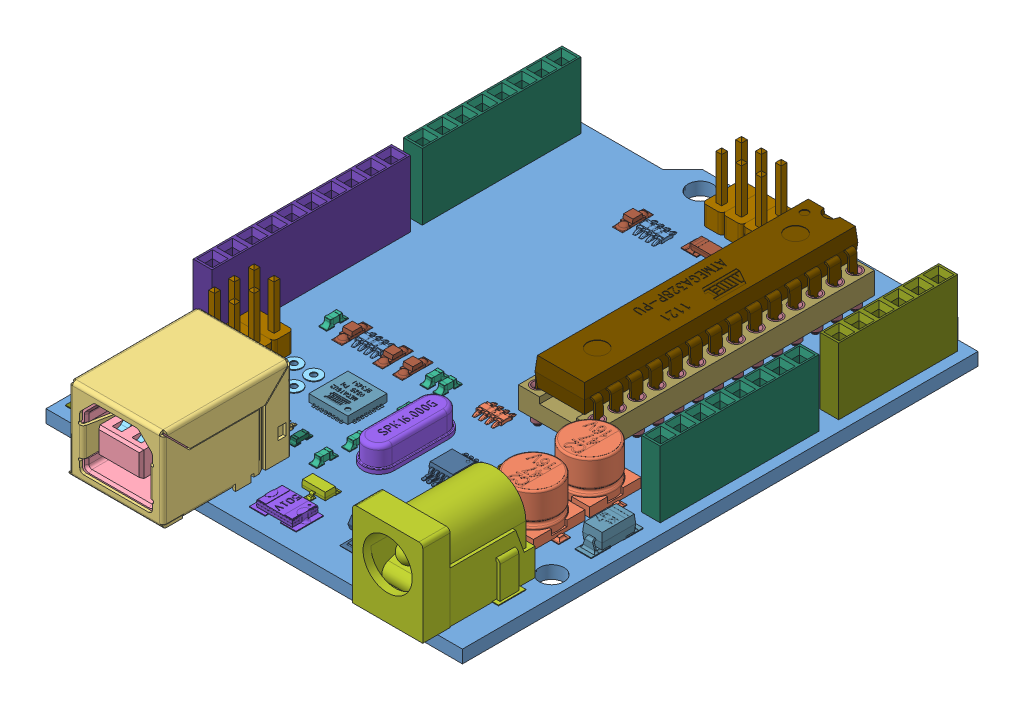
SolidWorks assembly 100001-10001-3-0, configuration Default. Lengths in mm.
Overall size (53.34 15.25 74.97).
87 component instances, 35 part files, 133 mates.
Components (placement in the parent):
- unoboar100001-10001-3-0 blue.SL100001-10001-3-0PRT-1: unoboar100001-10001-3-0 blue.SL100001-10001-3-0PRT [Default] at origin size (53.34 1.65 68.58)
- 47uf CAP 100001-10001-3-0case.SL100001-10001-3-0PRT-1: 47uf CAP 100001-10001-3-0case.SL100001-10001-3-0PRT [Default] at (-9.4141 0 -18.4991) x (0 0 -1) z (1 0 0) size (6.6 5.81 8)
- USB type b.SL100001-10001-3-0PRT.SL100001-10001-3-0ASM-1: USB type b.SL100001-10001-3-0PRT.SL100001-10001-3-0ASM [Default] at (-38.02 0.43 6.35) size (14.34 15.2 16.54)
  - USB SHELL.SL100001-10001-3-0PRT-1: USB SHELL.SL100001-10001-3-0PRT [Default] at origin size (14.34 15.2 16.54)
  - USB core.SL100001-10001-3-0PRT-1: USB core.SL100001-10001-3-0PRT [Default] at origin size (11.3 10.68 15.75)
  - usb top contact.SL100001-10001-3-0PRT-1: usb top contact.SL100001-10001-3-0PRT [Default] at (1.25 6.09 -0.38) size (1 9.67 13.76)
  - usb btm contact.SL100001-10001-3-0PRT-1: usb btm contact.SL100001-10001-3-0PRT [Default] at (1.25 4.41 -0.38) size (1 6.84 11.76)
  - usb btm contact.SL100001-10001-3-0PRT-2: usb btm contact.SL100001-10001-3-0PRT [Default] at (-1.25 4.41 -0.38) size (1 6.84 11.76)
  - usb top contact.SL100001-10001-3-0PRT-2: usb top contact.SL100001-10001-3-0PRT [Default] at (-1.25 6.09 -0.38) size (1 9.67 13.76)
- power jack.SL100001-10001-3-0PRT-1: power jack.SL100001-10001-3-0PRT [Default] at (-7.675 0 1.905) size (11.2 15.2 15.9)
- 47uf CAP 100001-10001-3-0case.SL100001-10001-3-0PRT-2: 47uf CAP 100001-10001-3-0case.SL100001-10001-3-0PRT [Default] at (-9.4141 0 -25.7132) x (0 0 -1) z (1 0 0) size (6.6 5.81 8)
- crystal.sl100001-10001-3-0prt-1: crystal.sl100001-10001-3-0prt [Default] at (-26.162 0 -18.923) x (1 0 0) z (0 0 -1) size (4 5 11)
- 2pin_hea100001-10001-3-0er__02.sl100001-10001-3-0prt-1: 2pin_hea100001-10001-3-0er__02.sl100001-10001-3-0prt [Default] at (-46.23 0 -15.75) size (5 11.75 2.54)
- nano - reg.SL100001-10001-3-0PRT-1: nano - reg.SL100001-10001-3-0PRT [Default] at (-17.399 0 -7.747) size (6.5 1.69 8.3)
- le100001-10001-3-0.SL100001-10001-3-0PRT-1: le100001-10001-3-0.SL100001-10001-3-0PRT [Default] at (-34.29 0 -27.94) x (0 0 1) z (-1 0 0) size (4 0.86 1.35)
- 2pin_hea100001-10001-3-0er__02.sl100001-10001-3-0prt-7: 2pin_hea100001-10001-3-0er__02.sl100001-10001-3-0prt [Default] at (-30.43 0 -64.91) x (0 0 1) z (-1 0 0) size (5 11.75 2.54)
- 100001-10001-3-0ip28.SL100001-10001-3-0ASM-1: 100001-10001-3-0ip28.SL100001-10001-3-0ASM [Default] at (-16.383 1.5 -46.355) x (0 0 -1) z (1 0 0) size (35.48 7.37 10.1)
  - 100001-10001-3-0ip28.SL100001-10001-3-0PRT-1: 100001-10001-3-0ip28.SL100001-10001-3-0PRT [Default] at origin size (35.48 2.8 10.1)
  - 100001-10001-3-0ip socket pin.SL100001-10001-3-0PRT-1: 100001-10001-3-0ip socket pin.SL100001-10001-3-0PRT [Default] at (16.51 2.8 -3.81) size (1.7 7.37 1.7)
  - 100001-10001-3-0ip socket pin.SL100001-10001-3-0PRT-2: 100001-10001-3-0ip socket pin.SL100001-10001-3-0PRT [Default] at (16.51 2.8 3.81) size (1.7 7.37 1.7)
  - 100001-10001-3-0ip socket pin.SL100001-10001-3-0PRT-3: 100001-10001-3-0ip socket pin.SL100001-10001-3-0PRT [Default] at (13.97 2.8 -3.81) size (1.7 7.37 1.7)
  - 100001-10001-3-0ip socket pin.SL100001-10001-3-0PRT-4: 100001-10001-3-0ip socket pin.SL100001-10001-3-0PRT [Default] at (13.97 2.8 3.81) size (1.7 7.37 1.7)
  - 100001-10001-3-0ip socket pin.SL100001-10001-3-0PRT-5: 100001-10001-3-0ip socket pin.SL100001-10001-3-0PRT [Default] at (11.43 2.8 -3.81) size (1.7 7.37 1.7)
  - 100001-10001-3-0ip socket pin.SL100001-10001-3-0PRT-6: 100001-10001-3-0ip socket pin.SL100001-10001-3-0PRT [Default] at (11.43 2.8 3.81) size (1.7 7.37 1.7)
  - 100001-10001-3-0ip socket pin.SL100001-10001-3-0PRT-7: 100001-10001-3-0ip socket pin.SL100001-10001-3-0PRT [Default] at (8.89 2.8 -3.81) size (1.7 7.37 1.7)
  - 100001-10001-3-0ip socket pin.SL100001-10001-3-0PRT-8: 100001-10001-3-0ip socket pin.SL100001-10001-3-0PRT [Default] at (8.89 2.8 3.81) size (1.7 7.37 1.7)
  - 100001-10001-3-0ip socket pin.SL100001-10001-3-0PRT-9: 100001-10001-3-0ip socket pin.SL100001-10001-3-0PRT [Default] at (6.35 2.8 -3.81) size (1.7 7.37 1.7)
  - 100001-10001-3-0ip socket pin.SL100001-10001-3-0PRT-10: 100001-10001-3-0ip socket pin.SL100001-10001-3-0PRT [Default] at (6.35 2.8 3.81) size (1.7 7.37 1.7)
  - 100001-10001-3-0ip socket pin.SL100001-10001-3-0PRT-11: 100001-10001-3-0ip socket pin.SL100001-10001-3-0PRT [Default] at (3.81 2.8 -3.81) size (1.7 7.37 1.7)
  - 100001-10001-3-0ip socket pin.SL100001-10001-3-0PRT-12: 100001-10001-3-0ip socket pin.SL100001-10001-3-0PRT [Default] at (3.81 2.8 3.81) size (1.7 7.37 1.7)
  - 100001-10001-3-0ip socket pin.SL100001-10001-3-0PRT-13: 100001-10001-3-0ip socket pin.SL100001-10001-3-0PRT [Default] at (1.27 2.8 -3.81) size (1.7 7.37 1.7)
  - 100001-10001-3-0ip socket pin.SL100001-10001-3-0PRT-14: 100001-10001-3-0ip socket pin.SL100001-10001-3-0PRT [Default] at (1.27 2.8 3.81) size (1.7 7.37 1.7)
  - 100001-10001-3-0ip socket pin.SL100001-10001-3-0PRT-15: 100001-10001-3-0ip socket pin.SL100001-10001-3-0PRT [Default] at (-1.27 2.8 -3.81) size (1.7 7.37 1.7)
  - 100001-10001-3-0ip socket pin.SL100001-10001-3-0PRT-16: 100001-10001-3-0ip socket pin.SL100001-10001-3-0PRT [Default] at (-1.27 2.8 3.81) size (1.7 7.37 1.7)
  - 100001-10001-3-0ip socket pin.SL100001-10001-3-0PRT-17: 100001-10001-3-0ip socket pin.SL100001-10001-3-0PRT [Default] at (-3.81 2.8 -3.81) size (1.7 7.37 1.7)
  - 100001-10001-3-0ip socket pin.SL100001-10001-3-0PRT-18: 100001-10001-3-0ip socket pin.SL100001-10001-3-0PRT [Default] at (-3.81 2.8 3.81) size (1.7 7.37 1.7)
  - 100001-10001-3-0ip socket pin.SL100001-10001-3-0PRT-19: 100001-10001-3-0ip socket pin.SL100001-10001-3-0PRT [Default] at (-6.35 2.8 -3.81) size (1.7 7.37 1.7)
  - 100001-10001-3-0ip socket pin.SL100001-10001-3-0PRT-20: 100001-10001-3-0ip socket pin.SL100001-10001-3-0PRT [Default] at (-6.35 2.8 3.81) size (1.7 7.37 1.7)
  - 100001-10001-3-0ip socket pin.SL100001-10001-3-0PRT-21: 100001-10001-3-0ip socket pin.SL100001-10001-3-0PRT [Default] at (-8.89 2.8 -3.81) size (1.7 7.37 1.7)
  - 100001-10001-3-0ip socket pin.SL100001-10001-3-0PRT-22: 100001-10001-3-0ip socket pin.SL100001-10001-3-0PRT [Default] at (-8.89 2.8 3.81) size (1.7 7.37 1.7)
  - 100001-10001-3-0ip socket pin.SL100001-10001-3-0PRT-23: 100001-10001-3-0ip socket pin.SL100001-10001-3-0PRT [Default] at (-11.43 2.8 -3.81) size (1.7 7.37 1.7)
  - 100001-10001-3-0ip socket pin.SL100001-10001-3-0PRT-24: 100001-10001-3-0ip socket pin.SL100001-10001-3-0PRT [Default] at (-11.43 2.8 3.81) size (1.7 7.37 1.7)
  - 100001-10001-3-0ip socket pin.SL100001-10001-3-0PRT-25: 100001-10001-3-0ip socket pin.SL100001-10001-3-0PRT [Default] at (-13.97 2.8 -3.81) size (1.7 7.37 1.7)
  - 100001-10001-3-0ip socket pin.SL100001-10001-3-0PRT-26: 100001-10001-3-0ip socket pin.SL100001-10001-3-0PRT [Default] at (-13.97 2.8 3.81) size (1.7 7.37 1.7)
  - 100001-10001-3-0ip socket pin.SL100001-10001-3-0PRT-27: 100001-10001-3-0ip socket pin.SL100001-10001-3-0PRT [Default] at (-16.51 2.8 -3.81) size (1.7 7.37 1.7)
  - 100001-10001-3-0ip socket pin.SL100001-10001-3-0PRT-28: 100001-10001-3-0ip socket pin.SL100001-10001-3-0PRT [Default] at (-16.51 2.8 3.81) size (1.7 7.37 1.7)
- 2pin_hea100001-10001-3-0er__02.sl100001-10001-3-0prt-8: 2pin_hea100001-10001-3-0er__02.sl100001-10001-3-0prt [Default] at (-27.89 0 -64.91) x (0 0 1) z (-1 0 0) size (5 11.75 2.54)
- 2pin_hea100001-10001-3-0er__02.sl100001-10001-3-0prt-9: 2pin_hea100001-10001-3-0er__02.sl100001-10001-3-0prt [Default] at (-25.35 0 -64.91) x (0 0 1) z (-1 0 0) size (5 11.75 2.54)
- 2pin_hea100001-10001-3-0er__02.sl100001-10001-3-0prt-5: 2pin_hea100001-10001-3-0er__02.sl100001-10001-3-0prt [Default] at (-46.23 0 -18.29) size (5 11.75 2.54)
- 2pin_hea100001-10001-3-0er__02.sl100001-10001-3-0prt-6: 2pin_hea100001-10001-3-0er__02.sl100001-10001-3-0prt [Default] at (-46.23 0 -20.83) size (5 11.75 2.54)
- atmega16u2.SL100001-10001-3-0PRT-1: atmega16u2.SL100001-10001-3-0PRT [Default] at (-34.671 0.06 -20) x (1 0 0) z (0 0 -1) size (5.5 1.01 5.5)
- le100001-10001-3-0.SL100001-10001-3-0PRT-2: le100001-10001-3-0.SL100001-10001-3-0PRT [Default] at (-36.83 0 -27.94) x (0 0 1) z (-1 0 0) size (4 0.86 1.35)
- le100001-10001-3-0.SL100001-10001-3-0PRT-3: le100001-10001-3-0.SL100001-10001-3-0PRT [Default] at (-42.037 0 -27.94) x (0 0 1) z (-1 0 0) size (4 0.86 1.35)
- le100001-10001-3-0.SL100001-10001-3-0PRT-4: le100001-10001-3-0.SL100001-10001-3-0PRT [Default] at (-36.576 0 -58.42) x (0 0 1) z (-1 0 0) size (4 0.86 1.35)
- 8 PORT HEA100001-10001-3-0ER.SL100001-10001-3-0PRT-3: 8 PORT HEA100001-10001-3-0ER.SL100001-10001-3-0PRT [Default] at (-50.8 0 -45.72) x (0 0 -1) z (1 0 0) size (20.32 10.51 2.41)
- 8 PORT HEA100001-10001-3-0ER.SL100001-10001-3-0PRT-4: 8 PORT HEA100001-10001-3-0ER.SL100001-10001-3-0PRT [Default] at (-2.54 0 -27.94) x (0 0 -1) z (1 0 0) size (20.32 10.51 2.41)
- 6 PORT HEA100001-10001-3-0ER.SL100001-10001-3-0PRT-3: 6 PORT HEA100001-10001-3-0ER.SL100001-10001-3-0PRT [Default] at (-2.54 0 -50.8) x (0 0 -1) z (1 0 0) size (15.24 10.51 2.41)
- 10 PORT HEA100001-10001-3-0ER.SL100001-10001-3-0PRT-1: 10 PORT HEA100001-10001-3-0ER.SL100001-10001-3-0PRT [Default] at (-50.8 0 -18.796) x (0 0 -1) z (1 0 0) size (25.4 10.51 2.41)
- ATMEL328P.SL100001-10001-3-0PRT-1: ATMEL328P.SL100001-10001-3-0PRT [Default] at (-16.383 4.3 -46.355) x (0 0 -1) z (1 0 0) size (35 7.27 7.87)
- 102 RESISTOR PACK.SL100001-10001-3-0PRT-1: 102 RESISTOR PACK.SL100001-10001-3-0PRT [Default] at (-33.782 0 -58.42) size (3.2 0.46 3)
- 102 RESISTOR PACK.SL100001-10001-3-0PRT-2: 102 RESISTOR PACK.SL100001-10001-3-0PRT [Default] at (-39.37 0 -27.94) size (3.2 0.46 3)
- 103 RESISTOR PACK.SL100001-10001-3-0PRT-3: 103 RESISTOR PACK.SL100001-10001-3-0PRT [Default] at (-23.876 0 -27.94) size (3.2 0.46 3)
- 220 RESISTOR PACK.SL100001-10001-3-0PRT-1: 220 RESISTOR PACK.SL100001-10001-3-0PRT [Default] at (-36.83 0 -12.827) size (3.2 0.46 3)
- 16mhz crystal - measure100001-10001-3-0.SL100001-10001-3-0PRT-1: 16mhz crystal - measure100001-10001-3-0.SL100001-10001-3-0PRT [Default] at (-24.892 0 -41.275) x (0 0 -1) z (1 0 0) size (3.4 0.8 2)
- PA100001-10001-3-0S001.SL100001-10001-3-0PRT-1: PA100001-10001-3-0S001.SL100001-10001-3-0PRT [Default] at (-39.878 0.1 -18.288) x (-1 0 0) z (0 0 1) size (4.54 0.1 4.54)
- 603 cap on pa100001-10001-3-0.SL100001-10001-3-0PRT-1: 603 cap on pa100001-10001-3-0.SL100001-10001-3-0PRT [Default] at (-44.45 0 -27.94) x (0 0 -1) z (1 0 0) size (2.76 0.9 1.12)
- ssot3.SL100001-10001-3-0PRT-1: ssot3.SL100001-10001-3-0PRT [Default] at (-26.5 0 -8.128) x (-1 0 0) z (0 0 -1) size (3 1.13 3.09)
- mf-msmf050-2.SL100001-10001-3-0PRT-1: mf-msmf050-2.SL100001-10001-3-0PRT [Default] at (-26.5 0 -4.064) size (5.77 1.02 3.72)
- 603 cap on pa100001-10001-3-0.SL100001-10001-3-0PRT-2: 603 cap on pa100001-10001-3-0.SL100001-10001-3-0PRT [Default] at (-29.845 0 -27.94) x (0 0 -1) z (1 0 0) size (2.76 0.9 1.12)
- 603 cap on pa100001-10001-3-0.SL100001-10001-3-0PRT-3: 603 cap on pa100001-10001-3-0.SL100001-10001-3-0PRT [Default] at (-31.496 0 -27.94) x (0 0 -1) z (1 0 0) size (2.76 0.9 1.12)
- lmv358.SL100001-10001-3-0PRT-1: lmv358.SL100001-10001-3-0PRT [Default] at (-15.24 0 -21.971) x (0 0 -1) z (1 0 0) size (3.7 1.4 2.9)
- 603 cap on pa100001-10001-3-0.SL100001-10001-3-0PRT-4: 603 cap on pa100001-10001-3-0.SL100001-10001-3-0PRT [Default] at (-15.24 0 -18.415) size (2.76 0.9 1.12)
- 603 cap on pa100001-10001-3-0.SL100001-10001-3-0PRT-5: 603 cap on pa100001-10001-3-0.SL100001-10001-3-0PRT [Default] at (-29.845 0 -12.065) x (0 0 1) z (-1 0 0) size (2.76 0.9 1.12)
- 603 cap on pa100001-10001-3-0.SL100001-10001-3-0PRT-6: 603 cap on pa100001-10001-3-0.SL100001-10001-3-0PRT [Default] at (-29.591 0 -22.352) x (0 0 1) z (-1 0 0) size (2.76 0.9 1.12)
- 603 cap on pa100001-10001-3-0.SL100001-10001-3-0PRT-7: 603 cap on pa100001-10001-3-0.SL100001-10001-3-0PRT [Default] at (-29.591 0 -16.002) x (0 0 1) z (-1 0 0) size (2.76 0.9 1.12)
- 603 cap on pa100001-10001-3-0.SL100001-10001-3-0PRT-8: 603 cap on pa100001-10001-3-0.SL100001-10001-3-0PRT [Default] at (-41.91 0 -12.7) x (0 0 1) z (-1 0 0) size (2.76 0.9 1.12)
- lp2985100001-10001-3-0gkr.SL100001-10001-3-0PRT-1: lp2985100001-10001-3-0gkr.SL100001-10001-3-0PRT [Default] at (-20.32 0 -19.05) x (0 0 -1) z (1 0 0) size (5.85 1.1 3)
- c100001-10001-3-01206 100001-10001-3-0io100001-10001-3-0e.SL100001-10001-3-0PRT-1: c100001-10001-3-01206 100001-10001-3-0io100001-10001-3-0e.SL100001-10001-3-0PRT [Default] at (-27.94 0 -59.436) x (0 0 -1) z (1 0 0) size (2.07 0.96 5)
- c100001-10001-3-01206 100001-10001-3-0io100001-10001-3-0e.SL100001-10001-3-0PRT-2: c100001-10001-3-01206 100001-10001-3-0io100001-10001-3-0e.SL100001-10001-3-0PRT [Default] at (-46.228 0 -13.081) x (0 0 1) z (-1 0 0) size (2.07 0.96 5)
- 603 resistor.SL100001-10001-3-0PRT-1: 603 resistor.SL100001-10001-3-0PRT [Default] at (-29.591 0 -19.05) x (0 0 1) z (-1 0 0) size (2.36 0.61 1.03)
- blm21.SL100001-10001-3-0PRT-1: blm21.SL100001-10001-3-0PRT [Default] at (-45.085 0 -7.62) x (0 0 -1) z (1 0 0) size (2.76 0.95 1.32)
- m7 100001-10001-3-0io100001-10001-3-0e.SL100001-10001-3-0PRT-1: m7 100001-10001-3-0io100001-10001-3-0e.SL100001-10001-3-0PRT [Default] at (-2.794 0 -21.59) x (0 0 -1) z (1 0 0) size (6.66 2.35 2.5)
- MLC0603.SL100001-10001-3-0PRT-1: MLC0603.SL100001-10001-3-0PRT [Default] at (-33.655 0 -12.827) x (0 0 -1) z (1 0 0) size (2.36 0.6 1.03)
- MLC0603.SL100001-10001-3-0PRT-2: MLC0603.SL100001-10001-3-0PRT [Default] at (-39.37 0 -12.827) x (0 0 -1) z (1 0 0) size (2.36 0.6 1.03)
- RESET BUTTON.SL100001-10001-3-0ASM-1: RESET BUTTON.SL100001-10001-3-0ASM [Default] at (-49.403 0 -6.35) size (6.2 3.1 9.6)
  - RESET CORE.SL100001-10001-3-0PRT-1: RESET CORE.SL100001-10001-3-0PRT [Default] at (0 0.1 0) x (-1 0 0) z (0 0 -1) size (6.2 3.1 9.6)
  - RESET.SL100001-10001-3-0PRT-1: RESET.SL100001-10001-3-0PRT [Default] at (0 0.1 0) x (0 0 1) z (-1 0 0) size (7.3 2 6.2)
Mates (geometry in assembly coordinates):
- Distance1: distance = 1.905 mm aligned: plane of power jack.SL100001-10001-3-0PRT-1 through (-7.675 0 1.905) normal (0 0 1); plane of unoboar100001-10001-3-0 blue.SL100001-10001-3-0PRT-1 through (0 0 0) normal (0 0 1)
- Coincident2: coincident aligned: plane of unoboar100001-10001-3-0 blue.SL100001-10001-3-0PRT-1 through (0 0 0) normal (0 1 0); plane of power jack.SL100001-10001-3-0PRT-1 through (-7.675 0 1.905) normal (0 1 0)
- Coincident3: coincident anti-aligned: plane of unoboar100001-10001-3-0 blue.SL100001-10001-3-0PRT-1 through (0 0 0) normal (0 1 0); plane of USB type b.SL100001-10001-3-0PRT.SL100001-10001-3-0ASM-1/USB core.SL100001-10001-3-0PRT-1 through (-38.02 0 6.35) normal (0 -1 0)
- Distance2: distance = 6.35 mm aligned: plane of USB type b.SL100001-10001-3-0PRT.SL100001-10001-3-0ASM-1/USB SHELL.SL100001-10001-3-0PRT-1 through (-38.02 0.43 6.35) normal (0 0 1); plane of unoboar100001-10001-3-0 blue.SL100001-10001-3-0PRT-1 through (0 0 0) normal (0 0 1)
- Coincident5: coincident aligned: plane of unoboar100001-10001-3-0 blue.SL100001-10001-3-0PRT-1 through (0 0 0) normal (0 1 0); plane of 47uf CAP 100001-10001-3-0case.SL100001-10001-3-0PRT-1
- Parallel1: parallel anti-aligned: plane of unoboar100001-10001-3-0 blue.SL100001-10001-3-0PRT-1 through (0 0 0) normal (0 0 1); plane of 47uf CAP 100001-10001-3-0case.SL100001-10001-3-0PRT-1 through (-9.4141 0 -18.4991) normal (0 0 -1)
- Coincident7: coincident aligned: plane of 47uf CAP 100001-10001-3-0case.SL100001-10001-3-0PRT-1 through (-6.1141 1.5 -15.1991) normal (1 0 0); plane of 47uf CAP 100001-10001-3-0case.SL100001-10001-3-0PRT-2 through (-6.1141 1.5 -22.4132) normal (1 0 0)
- Coincident8: coincident anti-aligned: plane of unoboar100001-10001-3-0 blue.SL100001-10001-3-0PRT-1 through (0 0 0) normal (0 1 0); plane of 47uf CAP 100001-10001-3-0case.SL100001-10001-3-0PRT-2 through (-8.1891 0 -25.7132) normal (0 -1 0)
- Distance3: distance = 3.175 mm aligned: plane of power jack.SL100001-10001-3-0PRT-1 through (-3.175 10.5 -1.595) normal (1 0 0); plane of unoboar100001-10001-3-0 blue.SL100001-10001-3-0PRT-1 through (0 -1.65 0) normal (1 0 0)
- Distance4: distance = 32 mm aligned: plane of USB type b.SL100001-10001-3-0PRT.SL100001-10001-3-0ASM-1/USB SHELL.SL100001-10001-3-0PRT-1 through (-32 0.43 6.35) normal (1 0 0); plane of unoboar100001-10001-3-0 blue.SL100001-10001-3-0PRT-1 through (0 -1.65 0) normal (1 0 0)
- Coincident11: coincident anti-aligned: plane of unoboar100001-10001-3-0 blue.SL100001-10001-3-0PRT-1 through (0 0 0) normal (0 1 0); plane of crystal.sl100001-10001-3-0prt-1 through (-26.162 0 -22.423) normal (0 -1 0)
- Concentric1: concentric aligned: cylinder of unoboar100001-10001-3-0 blue.SL100001-10001-3-0PRT-1 through (-26.162 -10 -16.383) axis (0 1 0) radius 0.5; cylinder of crystal.sl100001-10001-3-0prt-1 through (-26.162 -2 -16.383) axis (0 1 0) radius 0.4
- Concentric2: concentric aligned: cylinder of unoboar100001-10001-3-0 blue.SL100001-10001-3-0PRT-1 through (-26.162 -10 -21.463) axis (0 1 0) radius 0.5; cylinder of crystal.sl100001-10001-3-0prt-1 through (-26.162 -2 -21.463) axis (0 1 0) radius 0.4
- Coincident12: coincident anti-aligned: plane of unoboar100001-10001-3-0 blue.SL100001-10001-3-0PRT-1 through (0 0 0) normal (0 1 0); plane of 2pin_hea100001-10001-3-0er__02.sl100001-10001-3-0prt-1 through (-44.23 0 -14.98) normal (0 -1 0)
- Distance5: distance = 15.75 mm aligned: plane of 2pin_hea100001-10001-3-0er__02.sl100001-10001-3-0prt-1 through (-46.23 0 -15.75) normal (0 0 1); plane of assembly through (0 0 0) normal (0 0 1)
- Distance6: distance = 46.23 mm aligned: plane of 2pin_hea100001-10001-3-0er__02.sl100001-10001-3-0prt-1 through (-46.23 0 -15.75) normal (1 0 0); plane of assembly through (0 0 0) normal (1 0 0)
- Coincident15: coincident anti-aligned: plane of unoboar100001-10001-3-0 blue.SL100001-10001-3-0PRT-1 through (0 0 0) normal (0 1 0); plane of 2pin_hea100001-10001-3-0er__02.sl100001-10001-3-0prt-7 through (-31.2 0 -62.91) normal (0 -1 0)
- Distance7: distance = 64.91 mm aligned: plane of 2pin_hea100001-10001-3-0er__02.sl100001-10001-3-0prt-7 through (-30.43 0 -64.91) normal (0 0 1); plane of assembly through (0 0 0) normal (0 0 1)
- Distance8: distance = 30.43 mm anti-aligned: plane of 2pin_hea100001-10001-3-0er__02.sl100001-10001-3-0prt-7 through (-30.43 0 -64.91) normal (-1 0 0); plane of assembly through (0 0 0) normal (1 0 0)
- Coincident19: coincident anti-aligned: plane of unoboar100001-10001-3-0 blue.SL100001-10001-3-0PRT-1 through (0 0 0) normal (0 1 0); plane of nano - reg.SL100001-10001-3-0PRT-1 through (-17.399 0 -7.747) normal (0 -1 0)
- Concentric3: concentric aligned: cylinder of unoboar100001-10001-3-0 blue.SL100001-10001-3-0PRT-1 through (-20.193 -10 -62.865) axis (0 1 0) radius 0.4; cylinder of 100001-10001-3-0ip28.SL100001-10001-3-0ASM-1/100001-10001-3-0ip socket pin.SL100001-10001-3-0PRT-1 through (-20.193 33.2926 -62.865) axis (0 1 0) radius 0.25
- Concentric4: concentric aligned: cylinder of unoboar100001-10001-3-0 blue.SL100001-10001-3-0PRT-1 through (-12.573 -10 -29.845) axis (0 1 0) radius 0.4; cylinder of 100001-10001-3-0ip28.SL100001-10001-3-0ASM-1/100001-10001-3-0ip socket pin.SL100001-10001-3-0PRT-28 through (-12.573 33.2926 -29.845) axis (0 1 0) radius 0.25
- Distance9: distance = 1.5 mm anti-aligned: plane of 100001-10001-3-0ip28.SL100001-10001-3-0ASM-1/100001-10001-3-0ip28.SL100001-10001-3-0PRT-1 through (-11.333 1.5 -64.095) normal (0 -1 0); plane of unoboar100001-10001-3-0 blue.SL100001-10001-3-0PRT-1 through (0 0 0) normal (0 1 0)
- Coincident21: coincident anti-aligned: plane of unoboar100001-10001-3-0 blue.SL100001-10001-3-0PRT-1 through (0 0 0) normal (0 1 0); plane of atmega16u2.SL100001-10001-3-0PRT-1 through (-34.671 0 -20) normal (0 -1 0)
- Distance10: distance = 20 mm anti-aligned: plane of atmega16u2.SL100001-10001-3-0PRT-1 through (-34.671 0.06 -20) normal (0 0 -1); plane of unoboar100001-10001-3-0 blue.SL100001-10001-3-0PRT-1 through (0 0 0) normal (0 0 1)
- Distance11: distance = 34.671 mm aligned: plane of atmega16u2.SL100001-10001-3-0PRT-1; plane of unoboar100001-10001-3-0 blue.SL100001-10001-3-0PRT-1 through (0 0 0) normal (1 0 0)
- Coincident25: coincident anti-aligned: plane of unoboar100001-10001-3-0 blue.SL100001-10001-3-0PRT-1 through (0 0 0) normal (0 1 0); plane of le100001-10001-3-0.SL100001-10001-3-0PRT-1 through (-34.29 0 -28.94) normal (0 -1 0)
- Distance12: distance = 34.29 mm anti-aligned: plane of le100001-10001-3-0.SL100001-10001-3-0PRT-1 through (-34.29 0 -27.94) normal (-1 0 0); plane of unoboar100001-10001-3-0 blue.SL100001-10001-3-0PRT-1 through (0 0 0) normal (1 0 0)
- Distance13: distance = 27.94 mm aligned: plane of le100001-10001-3-0.SL100001-10001-3-0PRT-1 through (-34.29 0 -27.94) normal (0 0 1); plane of unoboar100001-10001-3-0 blue.SL100001-10001-3-0PRT-1 through (0 0 0) normal (0 0 1)
- Coincident28: coincident aligned: plane of le100001-10001-3-0.SL100001-10001-3-0PRT-2 through (-36.83 0 -28.94) normal (0 -1 0); plane of le100001-10001-3-0.SL100001-10001-3-0PRT-3 through (-42.037 0 -28.94) normal (0 -1 0)
- Coincident29: coincident aligned: plane of le100001-10001-3-0.SL100001-10001-3-0PRT-1 through (-34.29 0 -27.94) normal (0 0 1); plane of le100001-10001-3-0.SL100001-10001-3-0PRT-2 through (-36.83 0 -27.94) normal (0 0 1)
- Coincident30: coincident aligned: plane of le100001-10001-3-0.SL100001-10001-3-0PRT-1 through (-34.29 0 -27.94) normal (0 0 1); plane of le100001-10001-3-0.SL100001-10001-3-0PRT-3 through (-42.037 0 -27.94) normal (0 0 1)
- Distance14: distance = 2.54 mm aligned: plane of le100001-10001-3-0.SL100001-10001-3-0PRT-2 through (-36.83 0 -27.94) normal (-1 0 0); plane of le100001-10001-3-0.SL100001-10001-3-0PRT-1 through (-34.29 0 -27.94) normal (-1 0 0)
- Coincident32: coincident anti-aligned: plane of unoboar100001-10001-3-0 blue.SL100001-10001-3-0PRT-1 through (0 0 0) normal (0 1 0); plane of le100001-10001-3-0.SL100001-10001-3-0PRT-2 through (-36.83 0 -28.94) normal (0 -1 0)
- Distance15: distance = 42.037 mm anti-aligned: plane of le100001-10001-3-0.SL100001-10001-3-0PRT-3 through (-42.037 0 -27.94) normal (-1 0 0); plane of unoboar100001-10001-3-0 blue.SL100001-10001-3-0PRT-1 through (0 0 0) normal (1 0 0)
- Coincident34: coincident anti-aligned: plane of unoboar100001-10001-3-0 blue.SL100001-10001-3-0PRT-1 through (0 0 0) normal (0 1 0); plane of le100001-10001-3-0.SL100001-10001-3-0PRT-4 through (-36.576 0 -59.42) normal (0 -1 0)
- Distance16: distance = 36.576 mm anti-aligned: plane of le100001-10001-3-0.SL100001-10001-3-0PRT-4 through (-36.576 0 -58.42) normal (-1 0 0); plane of unoboar100001-10001-3-0 blue.SL100001-10001-3-0PRT-1 through (0 0 0) normal (1 0 0)
- Distance17: distance = 58.42 mm aligned: plane of le100001-10001-3-0.SL100001-10001-3-0PRT-4 through (-36.576 0 -58.42) normal (0 0 1); plane of unoboar100001-10001-3-0 blue.SL100001-10001-3-0PRT-1 through (0 0 0) normal (0 0 1)
- Coincident37: coincident aligned: plane of unoboar100001-10001-3-0 blue.SL100001-10001-3-0PRT-1 through (0 0 0) normal (0 1 0); plane of 8 PORT HEA100001-10001-3-0ER.SL100001-10001-3-0PRT-4
- Coincident38: coincident aligned: plane of unoboar100001-10001-3-0 blue.SL100001-10001-3-0PRT-1 through (0 0 0) normal (0 1 0); plane of 8 PORT HEA100001-10001-3-0ER.SL100001-10001-3-0PRT-3
- Parallel2: parallel aligned: plane of unoboar100001-10001-3-0 blue.SL100001-10001-3-0PRT-1 through (0 0 0) normal (1 0 0); plane of 8 PORT HEA100001-10001-3-0ER.SL100001-10001-3-0PRT-4 through (-2.54 0 -27.94) normal (1 0 0)
- Parallel3: parallel aligned: plane of unoboar100001-10001-3-0 blue.SL100001-10001-3-0PRT-1 through (0 0 0) normal (1 0 0); plane of 8 PORT HEA100001-10001-3-0ER.SL100001-10001-3-0PRT-3 through (-50.8 0 -45.72) normal (1 0 0)
- Concentric5: concentric aligned: cylinder of unoboar100001-10001-3-0 blue.SL100001-10001-3-0PRT-1 through (-2.54 -1.65 -27.94) axis (0 1 0) radius 0.4; line of 8 PORT HEA100001-10001-3-0ER.SL100001-10001-3-0PRT-4 through (-2.54 -2.5255 -27.94) axis (0 1 0)
- Concentric6: concentric aligned: cylinder of unoboar100001-10001-3-0 blue.SL100001-10001-3-0PRT-1 through (-50.8 -1.65 -45.72) axis (0 1 0) radius 0.4; line of 8 PORT HEA100001-10001-3-0ER.SL100001-10001-3-0PRT-3 through (-50.8 -2.5255 -45.72) axis (0 1 0)
- Coincident43: coincident aligned: plane of unoboar100001-10001-3-0 blue.SL100001-10001-3-0PRT-1 through (0 0 0) normal (0 1 0); plane of 10 PORT HEA100001-10001-3-0ER.SL100001-10001-3-0PRT-1
- Coincident44: coincident aligned: plane of unoboar100001-10001-3-0 blue.SL100001-10001-3-0PRT-1 through (0 0 0) normal (0 1 0); plane of 6 PORT HEA100001-10001-3-0ER.SL100001-10001-3-0PRT-3
- Parallel4: parallel aligned: plane of unoboar100001-10001-3-0 blue.SL100001-10001-3-0PRT-1 through (0 0 0) normal (1 0 0); plane of 6 PORT HEA100001-10001-3-0ER.SL100001-10001-3-0PRT-3 through (-2.54 0 -50.8) normal (1 0 0)
- Parallel5: parallel aligned: plane of unoboar100001-10001-3-0 blue.SL100001-10001-3-0PRT-1 through (0 0 0) normal (1 0 0); plane of 10 PORT HEA100001-10001-3-0ER.SL100001-10001-3-0PRT-1 through (-50.8 0 -18.796) normal (1 0 0)
- Concentric7: concentric aligned: cylinder of unoboar100001-10001-3-0 blue.SL100001-10001-3-0PRT-1 through (-50.8 -1.65 -18.796) axis (0 1 0) radius 0.4; line of 10 PORT HEA100001-10001-3-0ER.SL100001-10001-3-0PRT-1 through (-50.8 -2.5255 -18.796) axis (0 1 0)
- Concentric9: concentric aligned: cylinder of unoboar100001-10001-3-0 blue.SL100001-10001-3-0PRT-1 through (-2.54 -1.65 -50.8) axis (0 1 0) radius 0.4; line of 6 PORT HEA100001-10001-3-0ER.SL100001-10001-3-0PRT-3 through (-2.54 -2.5255 -50.8) axis (0 1 0)
- Coincident50: coincident aligned: plane of 100001-10001-3-0ip28.SL100001-10001-3-0ASM-1/100001-10001-3-0ip28.SL100001-10001-3-0PRT-1 through (-16.383 1.5 -46.355) normal (0 0 -1); plane of ATMEL328P.SL100001-10001-3-0PRT-1 through (-16.383 4.3 -46.355) normal (0 0 -1)
- Coincident51: coincident aligned: plane of 100001-10001-3-0ip28.SL100001-10001-3-0ASM-1/100001-10001-3-0ip28.SL100001-10001-3-0PRT-1 through (-16.383 1.5 -46.355) normal (1 0 0); plane of ATMEL328P.SL100001-10001-3-0PRT-1 through (-16.383 4.3 -46.355) normal (1 0 0)
- Coincident52: coincident aligned: plane of 100001-10001-3-0ip28.SL100001-10001-3-0ASM-1/100001-10001-3-0ip28.SL100001-10001-3-0PRT-1 through (-11.333 4.3 -64.095) normal (0 1 0); plane of ATMEL328P.SL100001-10001-3-0PRT-1
- Distance18: distance = 7.747 mm: plane of nano - reg.SL100001-10001-3-0PRT-1 through (-17.399 0 -7.747) normal (0 0 1); line of unoboar100001-10001-3-0 blue.SL100001-10001-3-0PRT-1 through (-53.34 0 0) axis (1 0 0)
- Distance19: distance = 17.399 mm aligned: plane of nano - reg.SL100001-10001-3-0PRT-1 through (-17.399 0 -7.747) normal (1 0 0); plane of unoboar100001-10001-3-0 blue.SL100001-10001-3-0PRT-1 through (0 0 0) normal (1 0 0)
- Coincident55: coincident anti-aligned: plane of unoboar100001-10001-3-0 blue.SL100001-10001-3-0PRT-1 through (0 0 0) normal (0 1 0); plane of 102 RESISTOR PACK.SL100001-10001-3-0PRT-1 through (-33.982 0 -59.12) normal (0 -1 0)
- Distance20: distance = 33.782 mm aligned: plane of 102 RESISTOR PACK.SL100001-10001-3-0PRT-1 through (-33.782 0 -58.42) normal (1 0 0); plane of unoboar100001-10001-3-0 blue.SL100001-10001-3-0PRT-1 through (0 0 0) normal (1 0 0)
- Distance21: distance = 58.42 mm aligned: plane of 102 RESISTOR PACK.SL100001-10001-3-0PRT-1 through (-33.782 0 -58.42) normal (0 0 1); plane of unoboar100001-10001-3-0 blue.SL100001-10001-3-0PRT-1 through (0 0 0) normal (0 0 1)
- Coincident58: coincident aligned: plane of 102 RESISTOR PACK.SL100001-10001-3-0PRT-2 through (-39.37 0 -27.94) normal (0 1 0); plane of 103 RESISTOR PACK.SL100001-10001-3-0PRT-3 through (-23.876 0 -27.94) normal (0 1 0)
- Coincident59: coincident aligned: plane of unoboar100001-10001-3-0 blue.SL100001-10001-3-0PRT-1 through (0 0 0) normal (0 1 0); plane of 103 RESISTOR PACK.SL100001-10001-3-0PRT-3 through (-23.876 0 -27.94) normal (0 1 0)
- Coincident60: coincident aligned: plane of 102 RESISTOR PACK.SL100001-10001-3-0PRT-2 through (-39.37 0 -27.94) normal (0 0 1); plane of 103 RESISTOR PACK.SL100001-10001-3-0PRT-3 through (-23.876 0 -27.94) normal (0 0 1)
- Distance22: distance = 23.876 mm aligned: plane of 103 RESISTOR PACK.SL100001-10001-3-0PRT-3 through (-23.876 0 -27.94) normal (1 0 0); plane of unoboar100001-10001-3-0 blue.SL100001-10001-3-0PRT-1 through (0 0 0) normal (1 0 0)
- Distance23: distance = 39.37 mm aligned: plane of 102 RESISTOR PACK.SL100001-10001-3-0PRT-2 through (-39.37 0 -27.94) normal (1 0 0); plane of unoboar100001-10001-3-0 blue.SL100001-10001-3-0PRT-1 through (0 0 0) normal (1 0 0)
- Distance24: distance = 27.94 mm aligned: plane of 102 RESISTOR PACK.SL100001-10001-3-0PRT-2 through (-39.37 0 -27.94) normal (0 0 1); plane of unoboar100001-10001-3-0 blue.SL100001-10001-3-0PRT-1 through (0 0 0) normal (0 0 1)
- Distance25: distance = 12.827 mm aligned: plane of 220 RESISTOR PACK.SL100001-10001-3-0PRT-1 through (-36.83 0 -12.827) normal (0 0 1); plane of unoboar100001-10001-3-0 blue.SL100001-10001-3-0PRT-1 through (0 0 0) normal (0 0 1)
- Distance26: distance = 36.83 mm aligned: plane of 220 RESISTOR PACK.SL100001-10001-3-0PRT-1 through (-36.83 0 -12.827) normal (1 0 0); plane of unoboar100001-10001-3-0 blue.SL100001-10001-3-0PRT-1 through (0 0 0) normal (1 0 0)
- Coincident66: coincident aligned: plane of unoboar100001-10001-3-0 blue.SL100001-10001-3-0PRT-1 through (0 0 0) normal (0 1 0); plane of 220 RESISTOR PACK.SL100001-10001-3-0PRT-1 through (-36.83 0 -12.827) normal (0 1 0)
- Coincident67: coincident anti-aligned: plane of unoboar100001-10001-3-0 blue.SL100001-10001-3-0PRT-1 through (0 0 0) normal (0 1 0); plane of 16mhz crystal - measure100001-10001-3-0.SL100001-10001-3-0PRT-1 through (-24.892 0 -41.275) normal (0 -1 0)
- Distance27: distance = 41.275 mm anti-aligned: plane of 16mhz crystal - measure100001-10001-3-0.SL100001-10001-3-0PRT-1 through (-24.892 0 -41.275) normal (0 0 -1); plane of unoboar100001-10001-3-0 blue.SL100001-10001-3-0PRT-1 through (0 0 0) normal (0 0 1)
- Distance28: distance = 24.892 mm aligned: plane of 16mhz crystal - measure100001-10001-3-0.SL100001-10001-3-0PRT-1 through (-24.892 0 -41.275) normal (1 0 0); plane of unoboar100001-10001-3-0 blue.SL100001-10001-3-0PRT-1 through (0 0 0) normal (1 0 0)
- Coincident70: coincident anti-aligned: plane of unoboar100001-10001-3-0 blue.SL100001-10001-3-0PRT-1 through (0 0 0) normal (0 1 0); plane of PA100001-10001-3-0S001.SL100001-10001-3-0PRT-1 through (-42.418 0 -18.288) normal (0 -1 0)
- Distance29: distance = 18.288 mm aligned: plane of PA100001-10001-3-0S001.SL100001-10001-3-0PRT-1 through (-39.878 0.1 -18.288) normal (0 0 1); plane of unoboar100001-10001-3-0 blue.SL100001-10001-3-0PRT-1 through (0 0 0) normal (0 0 1)
- Distance30: distance = 39.878 mm anti-aligned: plane of PA100001-10001-3-0S001.SL100001-10001-3-0PRT-1; plane of unoboar100001-10001-3-0 blue.SL100001-10001-3-0PRT-1 through (0 0 0) normal (1 0 0)
- Distance31: distance = 4.064 mm aligned: plane of mf-msmf050-2.SL100001-10001-3-0PRT-1 through (-26.5 0 -4.064) normal (0 0 1); plane of unoboar100001-10001-3-0 blue.SL100001-10001-3-0PRT-1 through (0 0 0) normal (0 0 1)
- Distance32: distance = 26.5 mm aligned: plane of mf-msmf050-2.SL100001-10001-3-0PRT-1 through (-26.5 0 -4.064) normal (1 0 0); plane of unoboar100001-10001-3-0 blue.SL100001-10001-3-0PRT-1 through (0 0 0) normal (1 0 0)
- Coincident72: coincident aligned: plane of unoboar100001-10001-3-0 blue.SL100001-10001-3-0PRT-1 through (0 0 0) normal (0 1 0); plane of mf-msmf050-2.SL100001-10001-3-0PRT-1 through (-26.5 0 -4.064) normal (0 1 0)
- Distance33: distance = 8.128 mm anti-aligned: plane of unoboar100001-10001-3-0 blue.SL100001-10001-3-0PRT-1 through (0 0 0) normal (0 0 1); plane of ssot3.SL100001-10001-3-0PRT-1 through (-26.5 0 -8.128) normal (0 0 -1)
- Coincident74: coincident anti-aligned: plane of ssot3.SL100001-10001-3-0PRT-1 through (-26.5 0 -8.128) normal (-1 0 0); plane of mf-msmf050-2.SL100001-10001-3-0PRT-1 through (-26.5 0 -4.064) normal (1 0 0)
- Coincident75: coincident aligned: plane of unoboar100001-10001-3-0 blue.SL100001-10001-3-0PRT-1 through (0 0 0) normal (0 1 0); plane of ssot3.SL100001-10001-3-0PRT-1
- Coincident76: coincident anti-aligned: plane of le100001-10001-3-0.SL100001-10001-3-0PRT-1 through (-34.29 0 -27.94) normal (0 0 1); plane of 603 cap on pa100001-10001-3-0.SL100001-10001-3-0PRT-1 through (-44.45 0 -27.94) normal (0 0 -1)
- Coincident77: coincident aligned: plane of unoboar100001-10001-3-0 blue.SL100001-10001-3-0PRT-1 through (0 0 0) normal (0 1 0); plane of 603 cap on pa100001-10001-3-0.SL100001-10001-3-0PRT-1
- Distance34: distance = 44.45 mm aligned: plane of 603 cap on pa100001-10001-3-0.SL100001-10001-3-0PRT-1 through (-44.45 0 -27.94) normal (1 0 0); plane of unoboar100001-10001-3-0 blue.SL100001-10001-3-0PRT-1 through (0 0 0) normal (1 0 0)
- Coincident79: coincident aligned: plane of 603 cap on pa100001-10001-3-0.SL100001-10001-3-0PRT-2; plane of 603 cap on pa100001-10001-3-0.SL100001-10001-3-0PRT-3
- Coincident80: coincident aligned: plane of 603 cap on pa100001-10001-3-0.SL100001-10001-3-0PRT-2 through (-29.845 0 -27.94) normal (0 0 -1); plane of 603 cap on pa100001-10001-3-0.SL100001-10001-3-0PRT-3 through (-31.496 0 -27.94) normal (0 0 -1)
- Coincident81: coincident aligned: plane of unoboar100001-10001-3-0 blue.SL100001-10001-3-0PRT-1 through (0 0 0) normal (0 1 0); plane of 603 cap on pa100001-10001-3-0.SL100001-10001-3-0PRT-2
- Coincident82: coincident aligned: plane of 603 cap on pa100001-10001-3-0.SL100001-10001-3-0PRT-1 through (-44.45 0 -27.94) normal (0 0 -1); plane of 603 cap on pa100001-10001-3-0.SL100001-10001-3-0PRT-2 through (-29.845 0 -27.94) normal (0 0 -1)
- Distance36: distance = 29.845 mm aligned: plane of 603 cap on pa100001-10001-3-0.SL100001-10001-3-0PRT-2 through (-29.845 0 -27.94) normal (1 0 0); plane of unoboar100001-10001-3-0 blue.SL100001-10001-3-0PRT-1 through (0 0 0) normal (1 0 0)
- Distance37: distance = 31.496 mm aligned: plane of 603 cap on pa100001-10001-3-0.SL100001-10001-3-0PRT-3 through (-31.496 0 -27.94) normal (1 0 0); plane of unoboar100001-10001-3-0 blue.SL100001-10001-3-0PRT-1 through (0 0 0) normal (1 0 0)
- Distance38: distance = 15.24 mm aligned: plane of unoboar100001-10001-3-0 blue.SL100001-10001-3-0PRT-1 through (0 0 0) normal (1 0 0); plane of lmv358.SL100001-10001-3-0PRT-1 through (-15.24 0 -21.971) normal (1 0 0)
- Distance39: distance = 21.971 mm anti-aligned: plane of lmv358.SL100001-10001-3-0PRT-1 through (-15.24 0 -21.971) normal (0 0 -1); plane of unoboar100001-10001-3-0 blue.SL100001-10001-3-0PRT-1 through (0 0 0) normal (0 0 1)
- Coincident88: coincident aligned: plane of unoboar100001-10001-3-0 blue.SL100001-10001-3-0PRT-1 through (0 0 0) normal (0 1 0); plane of lmv358.SL100001-10001-3-0PRT-1
- Distance40: distance = 18.415 mm aligned: plane of 603 cap on pa100001-10001-3-0.SL100001-10001-3-0PRT-4 through (-15.24 0 -18.415) normal (0 0 1); plane of unoboar100001-10001-3-0 blue.SL100001-10001-3-0PRT-1 through (0 0 0) normal (0 0 1)
- Distance41: distance = 15.24 mm aligned: plane of 603 cap on pa100001-10001-3-0.SL100001-10001-3-0PRT-4 through (-15.24 0 -18.415) normal (1 0 0); plane of unoboar100001-10001-3-0 blue.SL100001-10001-3-0PRT-1 through (0 0 0) normal (1 0 0)
- Coincident91: coincident aligned: plane of unoboar100001-10001-3-0 blue.SL100001-10001-3-0PRT-1 through (0 0 0) normal (0 1 0); plane of 603 cap on pa100001-10001-3-0.SL100001-10001-3-0PRT-4 through (-15.24 0 -18.415) normal (0 1 0)
- Coincident92: coincident aligned: plane of unoboar100001-10001-3-0 blue.SL100001-10001-3-0PRT-1 through (0 0 0) normal (0 1 0); plane of 603 cap on pa100001-10001-3-0.SL100001-10001-3-0PRT-7
- Coincident93: coincident aligned: plane of unoboar100001-10001-3-0 blue.SL100001-10001-3-0PRT-1 through (0 0 0) normal (0 1 0); plane of 603 cap on pa100001-10001-3-0.SL100001-10001-3-0PRT-6
- Coincident94: coincident aligned: plane of 603 cap on pa100001-10001-3-0.SL100001-10001-3-0PRT-5; plane of unoboar100001-10001-3-0 blue.SL100001-10001-3-0PRT-1 through (0 0 0) normal (0 1 0)
- Coincident95: coincident aligned: plane of 603 cap on pa100001-10001-3-0.SL100001-10001-3-0PRT-8; plane of unoboar100001-10001-3-0 blue.SL100001-10001-3-0PRT-1 through (0 0 0) normal (0 1 0)
- Coincident96: coincident aligned: plane of 603 cap on pa100001-10001-3-0.SL100001-10001-3-0PRT-7 through (-29.591 0 -16.002) normal (-1 0 0); plane of 603 cap on pa100001-10001-3-0.SL100001-10001-3-0PRT-6 through (-29.591 0 -22.352) normal (-1 0 0)
- Distance42: distance = 29.591 mm anti-aligned: plane of 603 cap on pa100001-10001-3-0.SL100001-10001-3-0PRT-7 through (-29.591 0 -16.002) normal (-1 0 0); plane of unoboar100001-10001-3-0 blue.SL100001-10001-3-0PRT-1 through (0 0 0) normal (1 0 0)
- Distance43: distance = 22.352 mm: plane of 603 cap on pa100001-10001-3-0.SL100001-10001-3-0PRT-6 through (-29.591 0 -22.352) normal (0 0 1); line of unoboar100001-10001-3-0 blue.SL100001-10001-3-0PRT-1 through (-53.34 0 0) axis (1 0 0)
- Distance44: distance = 16.002 mm aligned: plane of 603 cap on pa100001-10001-3-0.SL100001-10001-3-0PRT-7 through (-29.591 0 -16.002) normal (0 0 1); plane of unoboar100001-10001-3-0 blue.SL100001-10001-3-0PRT-1 through (0 0 0) normal (0 0 1)
- Distance45: distance = 29.845 mm anti-aligned: plane of 603 cap on pa100001-10001-3-0.SL100001-10001-3-0PRT-5 through (-29.845 0 -12.065) normal (-1 0 0); plane of unoboar100001-10001-3-0 blue.SL100001-10001-3-0PRT-1 through (0 0 0) normal (1 0 0)
- Distance46: distance = 12.065 mm aligned: plane of 603 cap on pa100001-10001-3-0.SL100001-10001-3-0PRT-5 through (-29.845 0 -12.065) normal (0 0 1); plane of unoboar100001-10001-3-0 blue.SL100001-10001-3-0PRT-1 through (0 0 0) normal (0 0 1)
- Distance47: distance = 41.91 mm anti-aligned: plane of 603 cap on pa100001-10001-3-0.SL100001-10001-3-0PRT-8 through (-41.91 0 -12.7) normal (-1 0 0); plane of unoboar100001-10001-3-0 blue.SL100001-10001-3-0PRT-1 through (0 0 0) normal (1 0 0)
- Distance48: distance = 12.7 mm aligned: plane of 603 cap on pa100001-10001-3-0.SL100001-10001-3-0PRT-8 through (-41.91 0 -12.7) normal (0 0 1); plane of unoboar100001-10001-3-0 blue.SL100001-10001-3-0PRT-1 through (0 0 0) normal (0 0 1)
- Distance49: distance = 20.32 mm aligned: plane of lp2985100001-10001-3-0gkr.SL100001-10001-3-0PRT-1 through (-20.32 0 -19.05) normal (1 0 0); plane of unoboar100001-10001-3-0 blue.SL100001-10001-3-0PRT-1 through (0 0 0) normal (1 0 0)
- Distance50: distance = 19.05 mm anti-aligned: plane of lp2985100001-10001-3-0gkr.SL100001-10001-3-0PRT-1 through (-20.32 0 -19.05) normal (0 0 -1); plane of unoboar100001-10001-3-0 blue.SL100001-10001-3-0PRT-1 through (0 0 0) normal (0 0 1)
- Coincident99: coincident aligned: plane of unoboar100001-10001-3-0 blue.SL100001-10001-3-0PRT-1 through (0 0 0) normal (0 1 0); plane of lp2985100001-10001-3-0gkr.SL100001-10001-3-0PRT-1
- Distance51: distance = 27.94 mm aligned: plane of c100001-10001-3-01206 100001-10001-3-0io100001-10001-3-0e.SL100001-10001-3-0PRT-1 through (-27.94 0 -59.436) normal (1 0 0); plane of unoboar100001-10001-3-0 blue.SL100001-10001-3-0PRT-1 through (0 0 0) normal (1 0 0)
- Distance52: distance = 59.436 mm anti-aligned: plane of c100001-10001-3-01206 100001-10001-3-0io100001-10001-3-0e.SL100001-10001-3-0PRT-1 through (-27.94 0 -59.436) normal (0 0 -1); plane of unoboar100001-10001-3-0 blue.SL100001-10001-3-0PRT-1 through (0 0 0) normal (0 0 1)
- Coincident102: coincident aligned: plane of unoboar100001-10001-3-0 blue.SL100001-10001-3-0PRT-1 through (0 0 0) normal (0 1 0); plane of c100001-10001-3-01206 100001-10001-3-0io100001-10001-3-0e.SL100001-10001-3-0PRT-1
- Distance53: distance = 46.228 mm anti-aligned: plane of c100001-10001-3-01206 100001-10001-3-0io100001-10001-3-0e.SL100001-10001-3-0PRT-2 through (-46.228 0 -13.081) normal (-1 0 0); plane of unoboar100001-10001-3-0 blue.SL100001-10001-3-0PRT-1 through (0 0 0) normal (1 0 0)
- Distance54: distance = 13.081 mm aligned: plane of unoboar100001-10001-3-0 blue.SL100001-10001-3-0PRT-1 through (0 0 0) normal (0 0 1); plane of c100001-10001-3-01206 100001-10001-3-0io100001-10001-3-0e.SL100001-10001-3-0PRT-2 through (-46.228 0 -13.081) normal (0 0 1)
- Coincident105: coincident aligned: plane of unoboar100001-10001-3-0 blue.SL100001-10001-3-0PRT-1 through (0 0 0) normal (0 1 0); plane of c100001-10001-3-01206 100001-10001-3-0io100001-10001-3-0e.SL100001-10001-3-0PRT-2
- Distance55: distance = 29.591 mm anti-aligned: plane of 603 resistor.SL100001-10001-3-0PRT-1 through (-29.591 0 -19.05) normal (-1 0 0); plane of unoboar100001-10001-3-0 blue.SL100001-10001-3-0PRT-1 through (0 0 0) normal (1 0 0)
- Distance56: distance = 19.05 mm aligned: plane of 603 resistor.SL100001-10001-3-0PRT-1 through (-29.591 0 -19.05) normal (0 0 1); plane of unoboar100001-10001-3-0 blue.SL100001-10001-3-0PRT-1 through (0 0 0) normal (0 0 1)
- Coincident108: coincident aligned: plane of unoboar100001-10001-3-0 blue.SL100001-10001-3-0PRT-1 through (0 0 0) normal (0 1 0); plane of 603 resistor.SL100001-10001-3-0PRT-1
- Distance57: distance = 7.62 mm anti-aligned: plane of blm21.SL100001-10001-3-0PRT-1 through (-45.085 0 -7.62) normal (0 0 -1); plane of unoboar100001-10001-3-0 blue.SL100001-10001-3-0PRT-1 through (0 0 0) normal (0 0 1)
- Distance58: distance = 45.085 mm aligned: plane of blm21.SL100001-10001-3-0PRT-1 through (-45.085 0 -7.62) normal (1 0 0); plane of unoboar100001-10001-3-0 blue.SL100001-10001-3-0PRT-1 through (0 0 0) normal (1 0 0)
- Distance59: distance = 21.59 mm anti-aligned: plane of m7 100001-10001-3-0io100001-10001-3-0e.SL100001-10001-3-0PRT-1 through (-2.794 0 -21.59) normal (0 0 -1); plane of unoboar100001-10001-3-0 blue.SL100001-10001-3-0PRT-1 through (0 0 0) normal (0 0 1)
- Distance60: distance = 2.794 mm aligned: plane of m7 100001-10001-3-0io100001-10001-3-0e.SL100001-10001-3-0PRT-1 through (-2.794 0 -21.59) normal (1 0 0); plane of unoboar100001-10001-3-0 blue.SL100001-10001-3-0PRT-1 through (0 0 0) normal (1 0 0)
- Coincident113: coincident aligned: plane of unoboar100001-10001-3-0 blue.SL100001-10001-3-0PRT-1 through (0 0 0) normal (0 1 0); plane of m7 100001-10001-3-0io100001-10001-3-0e.SL100001-10001-3-0PRT-1
- Coincident114: coincident anti-aligned: plane of 220 RESISTOR PACK.SL100001-10001-3-0PRT-1 through (-36.83 0 -12.827) normal (0 0 1); plane of MLC0603.SL100001-10001-3-0PRT-1 through (-33.655 0 -12.827) normal (0 0 -1)
- Distance61: distance = 33.655 mm aligned: plane of MLC0603.SL100001-10001-3-0PRT-1 through (-33.655 0 -12.827) normal (1 0 0); plane of unoboar100001-10001-3-0 blue.SL100001-10001-3-0PRT-1 through (0 0 0) normal (1 0 0)
- Coincident115: coincident aligned: plane of unoboar100001-10001-3-0 blue.SL100001-10001-3-0PRT-1 through (0 0 0) normal (0 1 0); plane of MLC0603.SL100001-10001-3-0PRT-1
- Coincident116: coincident aligned: plane of unoboar100001-10001-3-0 blue.SL100001-10001-3-0PRT-1 through (0 0 0) normal (0 1 0); plane of blm21.SL100001-10001-3-0PRT-1
- Coincident117: coincident anti-aligned: plane of 220 RESISTOR PACK.SL100001-10001-3-0PRT-1 through (-36.83 0 -12.827) normal (0 0 1); plane of MLC0603.SL100001-10001-3-0PRT-2 through (-39.37 0 -12.827) normal (0 0 -1)
- Coincident118: coincident aligned: plane of unoboar100001-10001-3-0 blue.SL100001-10001-3-0PRT-1 through (0 0 0) normal (0 1 0); plane of MLC0603.SL100001-10001-3-0PRT-2
- Distance62: distance = 39.37 mm aligned: plane of MLC0603.SL100001-10001-3-0PRT-2 through (-39.37 0 -12.827) normal (1 0 0); plane of unoboar100001-10001-3-0 blue.SL100001-10001-3-0PRT-1 through (0 0 0) normal (1 0 0)
- Distance63: distance = 49.403 mm aligned: plane of RESET BUTTON.SL100001-10001-3-0ASM-1 through (-49.403 0 -6.35) normal (1 0 0); plane of unoboar100001-10001-3-0 blue.SL100001-10001-3-0PRT-1 through (0 0 0) normal (1 0 0)
- Distance64: distance = 6.35 mm aligned: plane of RESET BUTTON.SL100001-10001-3-0ASM-1; plane of unoboar100001-10001-3-0 blue.SL100001-10001-3-0PRT-1 through (0 0 0) normal (0 0 1)
- Coincident122: coincident aligned: plane of unoboar100001-10001-3-0 blue.SL100001-10001-3-0PRT-1 through (0 0 0) normal (0 1 0); plane of RESET BUTTON.SL100001-10001-3-0ASM-1 through (-49.403 0 -6.35) normal (0 1 0)
